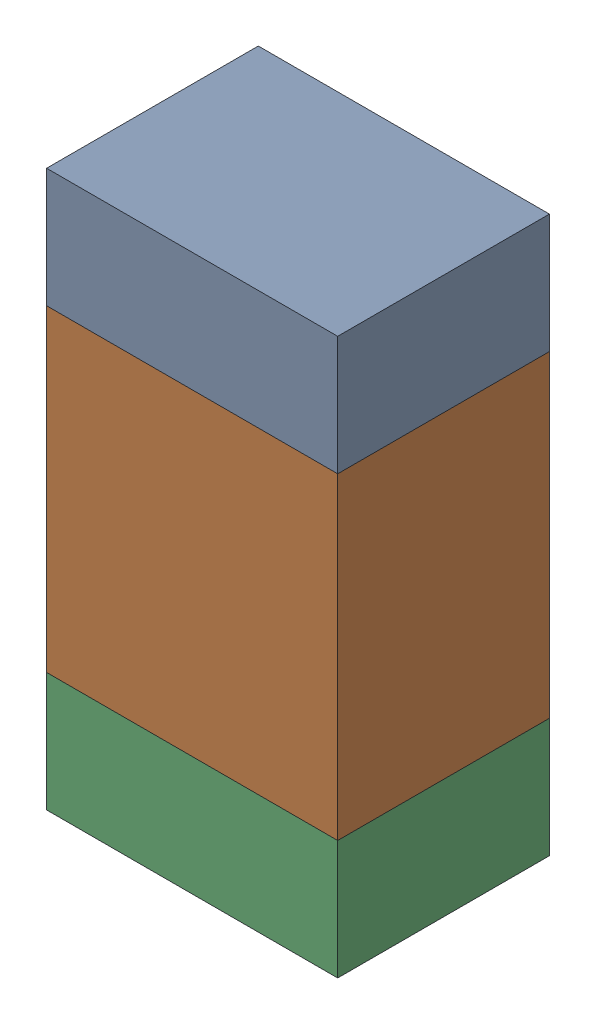
SolidWorks assembly R307_1PCB, configuration Default. Lengths in mm.
Overall size (0.55 1.05 0.4).
6 component instances, 2 part files, 0 mates.
Components (placement in the parent):
- 846483288-1: 846483288 [Default] at (136.2001 110.8124 0) size (0.55 0.22 0.4)
  - Extruded_12-1: Extruded_12 [Default] at origin size (0.55 0.22 0.4)
- 846483424-1: 846483424 [Default] at (136.2001 110.3999 0) size (0.55 0.6 0.4)
  - Extruded_13-1: Extruded_13 [Default] at origin size (0.55 0.6 0.4)
- 846483288-2: 846483288 [Default] at (136.2001 109.9874 0) size (0.55 0.22 0.4)
  - Extruded_12-1: Extruded_12 [Default] at origin size (0.55 0.22 0.4)
